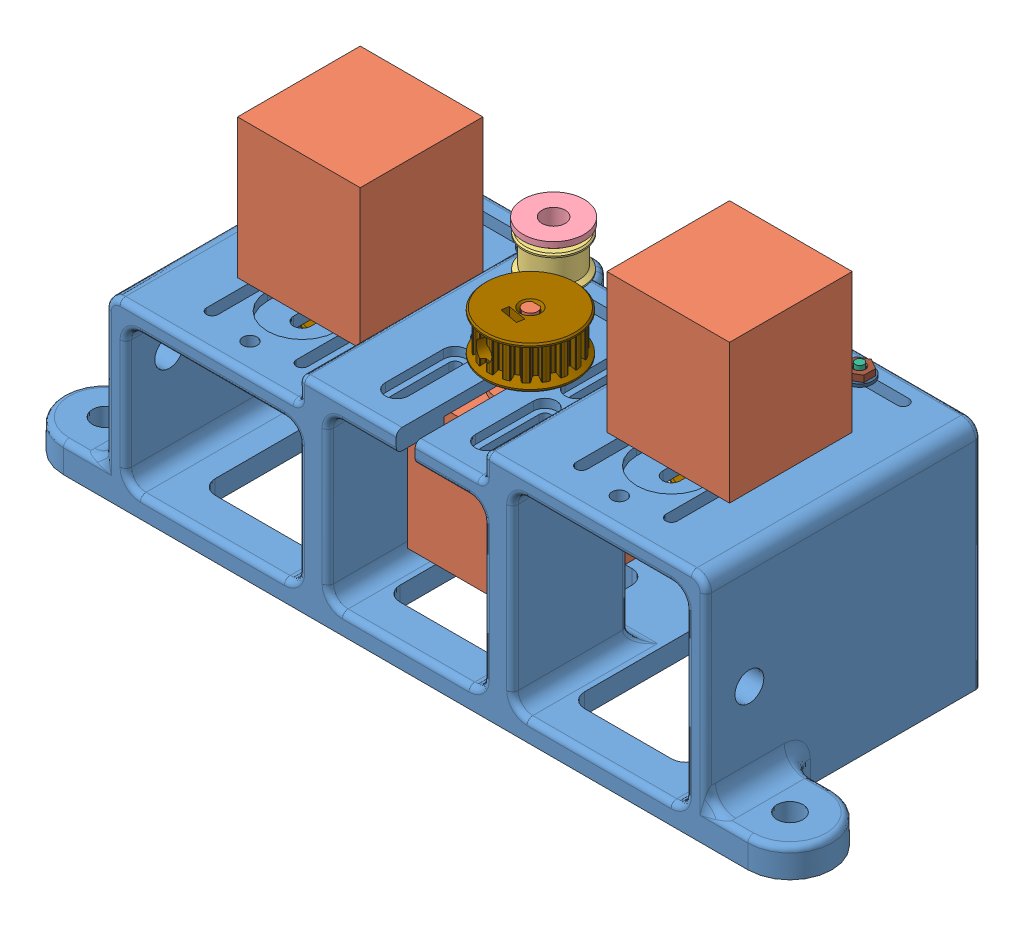
SolidWorks assembly stepper assembly, configuration Default. Lengths in mm.
Overall size (265 127.5 103.75).
53 component instances, 11 part files, 71 mates.
Components (placement in the parent):
- stepper holder for 790-2: stepper holder for 790 [Default] at origin size (265 79.5 95)
- stepper-1: stepper [Default] at (-63.6667 106.5 -0.5) x (1 0 0) z (0 0 -1) size (42.3 72 42.3)
- stepper-2: stepper [Default] at (0 12 4.5) size (42.3 72 42.3)
- stepper-3: stepper [Default] at (63.6667 124 -0.5) x (1 0 0) z (0 0 -1) size (42.3 72 42.3)
- belt tensioner assembly-1: belt tensioner assembly [Default] at (20 67 -23.5) x (-1 0 0) z (0 0 -1) size (27.67 31.4 27.67)
  - belt tensioner pulley-1: belt tensioner pulley [Default] at (0 9.75 0) x (-0.886174 0 0.463352) z (0 -1 0) size (20.5 20.5 12.5)
  - belt tensioner base-1: belt tensioner base [Default] at origin size (21 20 21)
  - M3 METAL washer-1: M3 METAL washer [Default] at (0 4 0) size (7 0.6 7)
  - M3x16 METAL bolt-1: M3x16 METAL bolt [Default] at (0 -11.4 0) x (-0.239711 0 0.970844) z (-0.970844 0 -0.239711) size (5.4 19 5.4)
- belt tensioner assembly-4: belt tensioner assembly [Default] at (-69.5 51.5 -39.5) x (-0.970844 0 -0.239711) z (-0.239711 0 0.970844) size (27.67 31.4 27.67)
  - belt tensioner pulley-1: belt tensioner pulley [Default] at (0 9.75 0) x (-0.886174 0 0.463352) z (0 -1 0) size (20.5 20.5 12.5)
  - belt tensioner base-1: belt tensioner base [Default] at origin size (21 20 21)
  - M3 METAL washer-1: M3 METAL washer [Default] at (0 4 0) size (7 0.6 7)
  - M3x16 METAL bolt-1: M3x16 METAL bolt [Default] at (0 -11.4 0) x (-0.239711 0 0.970844) z (-0.970844 0 -0.239711) size (5.4 19 5.4)
- belt tensioner assembly-6: belt tensioner assembly [Default] at (42.8333 69 -39.5) x (0.970844 0 0.239711) z (0.239711 0 -0.970844) size (27.67 31.4 27.67)
  - belt tensioner pulley-1: belt tensioner pulley [Default] at (0 9.75 0) x (-0.886174 0 0.463352) z (0 -1 0) size (20.5 20.5 12.5)
  - belt tensioner base-1: belt tensioner base [Default] at origin size (21 20 21)
  - M3 METAL washer-1: M3 METAL washer [Default] at (0 4 0) size (7 0.6 7)
  - M3x16 METAL bolt-1: M3x16 METAL bolt [Default] at (0 -11.4 0) x (-0.239711 0 0.970844) z (-0.970844 0 -0.239711) size (5.4 19 5.4)
- belt tensioner assembly-7: belt tensioner assembly [Default] at (69.5 69 -39.5) x (-0.970844 0 -0.239711) z (-0.239711 0 0.970844) size (27.67 31.4 27.67)
  - belt tensioner pulley-1: belt tensioner pulley [Default] at (0 9.75 0) x (-0.886174 0 0.463352) z (0 -1 0) size (20.5 20.5 12.5)
  - belt tensioner base-1: belt tensioner base [Default] at origin size (21 20 21)
  - M3 METAL washer-1: M3 METAL washer [Default] at (0 4 0) size (7 0.6 7)
  - M3x16 METAL bolt-1: M3x16 METAL bolt [Default] at (0 -11.4 0) x (-0.239711 0 0.970844) z (-0.970844 0 -0.239711) size (5.4 19 5.4)
- belt tensioner assembly-8: belt tensioner assembly [Default] at (-42.8333 51.5 -39.5) x (0.239711 0 -0.970844) z (-0.970844 0 -0.239711) size (27.67 31.4 27.67)
  - belt tensioner pulley-1: belt tensioner pulley [Default] at (0 9.75 0) x (-0.886174 0 0.463352) z (0 -1 0) size (20.5 20.5 12.5)
  - belt tensioner base-1: belt tensioner base [Default] at origin size (21 20 21)
  - M3 METAL washer-1: M3 METAL washer [Default] at (0 4 0) size (7 0.6 7)
  - M3x16 METAL bolt-1: M3x16 METAL bolt [Default] at (0 -11.4 0) x (-0.239711 0 0.970844) z (-0.970844 0 -0.239711) size (5.4 19 5.4)
- belt tensioner assembly-9: belt tensioner assembly [Default] at (-20 67 -23.5) x (-0.639531 0 -0.768765) z (0.768765 0 -0.639531) size (27.67 31.4 27.67)
  - belt tensioner pulley-1: belt tensioner pulley [Default] at (0 9.75 0) x (-0.886174 0 0.463352) z (0 -1 0) size (20.5 20.5 12.5)
  - belt tensioner base-1: belt tensioner base [Default] at origin size (21 20 21)
  - M3 METAL washer-1: M3 METAL washer [Default] at (0 4 0) size (7 0.6 7)
  - M3x16 METAL bolt-1: M3x16 METAL bolt [Default] at (0 -11.4 0) x (-0.239711 0 0.970844) z (-0.970844 0 -0.239711) size (5.4 19 5.4)
- M3x12 METAL bolt-1: M3x12 METAL bolt [Default] at (48.1667 83.4 -16) x (0.811733 0 0.584029) z (0.584029 0 -0.811733) size (5.4 15 5.4)
- M3 METAL washer-3: M3 METAL washer [Default] at (48.1667 71.4 -16) size (7 0.6 7)
- M3 METAL washer-4: M3 METAL washer [Default] at (-15.5 64.6 -11) x (-0.514541 0 0.857466) z (0.857466 0 0.514541) size (7 0.6 7)
- M3x8 METAL bolt-2: M3x8 METAL bolt [Default] at (-15.5 56.6 -11) x (-0.864445 0 -0.502727) z (0.502727 0 -0.864445) size (5.6 10.5 5.6)
- stepper pulley-1: stepper pulley [Default] at (0 76.75 4.5) x (-0.98678 0 -0.162068) z (0 -1 0) size (31.3 31.3 14.5)
- stepper pulley-2: stepper pulley [Default] at (63.6667 59.25 -0.5) x (0.991489 0 0.130188) z (0 1 0) size (31.3 31.3 14.5)
- stepper pulley-3: stepper pulley [Default] at (-63.6667 41.75 -0.5) x (-0.606605 0 -0.795004) z (0 1 0) size (31.3 31.3 14.5)
- plain washer 10669 type nl_iso-1: plain washer 10669 type nl_iso [ISO 10669-3.55-N] at (69.5 77 -39.5) x (0 -1 0) z (0 0 1) size (1 9 9)
- plain washer 10669 type nl_iso-2: plain washer 10669 type nl_iso [ISO 10669-3.55-N] at (42.8333 77 -39.5) x (0 -1 0) z (0 0 1) size (1 9 9)
- plain washer 10669 type nl_iso-3: plain washer 10669 type nl_iso [ISO 10669-3.55-N] at (20 59 -23.5) x (0 1 0) z (0 0 1) size (1 9 9)
- plain washer 10669 type nl_iso-4: plain washer 10669 type nl_iso [ISO 10669-3.55-N] at (-20 59 -23.5) x (0 1 0) z (0 0 1) size (1 9 9)
- plain washer 10669 type nl_iso-5: plain washer 10669 type nl_iso [ISO 10669-3.55-N] at (-42.8333 59.5 -39.5) x (0 -1 0) z (0 0 1) size (1 9 9)
- plain washer 10669 type nl_iso-6: plain washer 10669 type nl_iso [ISO 10669-3.55-N] at (-69.5 58.5 -39.5) x (0 1 0) z (0 0 1) size (1 9 9)
- hex thin nut gradeb_iso-1: hex thin nut gradeb_iso [ISO - 4036 - M4 - N] at (69.5 79.2 -39.5) x (1 0 0) z (0 1 0) size (7 8.08 2.2)
- hex thin nut gradeb_iso-2: hex thin nut gradeb_iso [ISO - 4036 - M4 - N] at (42.8333 79.2 -39.5) x (1 0 0) z (0 1 0) size (7 8.08 2.2)
- hex thin nut gradeb_iso-3: hex thin nut gradeb_iso [ISO - 4036 - M4 - N] at (-69.5 61.7 -39.5) x (1 0 0) z (0 1 0) size (7 8.08 2.2)
- hex thin nut gradeb_iso-4: hex thin nut gradeb_iso [ISO - 4036 - M4 - N] at (-42.8333 61.7 -39.5) x (1 0 0) z (0 1 0) size (7 8.08 2.2)
- hex thin nut gradeb_iso-5: hex thin nut gradeb_iso [ISO - 4036 - M4 - N] at (-20 56.8 -23.5) x (1 0 0) z (0 -1 0) size (7 8.08 2.2)
- hex thin nut gradeb_iso-6: hex thin nut gradeb_iso [ISO - 4036 - M4 - N] at (20 56.8 -23.5) x (1 0 0) z (0 -1 0) size (7 8.08 2.2)
Mates (geometry in assembly coordinates):
- Coincident26: coordinate: point of stepper holder-1
- Symmetric1: symmetric aligned: plane of stepper holder for 790-2 through (-51.6667 36 19.5) normal (-1 0 0); plane of stepper holder for 790-2 through (-75.6667 36 19.5) normal (1 0 0); plane of stepper-1 through (-63.6667 106.5 -0.5) normal (1 0 0)
- Coincident27: coincident anti-aligned: plane of stepper holder for 790-2 through (0 58.5 47.5) normal (0 1 0); plane of stepper-1 through (-63.6667 58.5 -0.5) normal (0 -1 0)
- Symmetric4: symmetric aligned: plane of stepper holder for 790-2 through (75.6667 36 19.5) normal (-1 0 0); plane of stepper holder for 790-2 through (51.6667 36 19.5) normal (1 0 0); plane of stepper-3 through (63.6667 124 -0.5) normal (1 0 0)
- Symmetric5: symmetric aligned: plane of stepper holder for 790-2 through (-12 27 19.5) normal (1 0 0); plane of stepper holder for 790-2 through (12 27 19.5) normal (-1 0 0); plane of stepper-2 through (0 12 11.9177) normal (1 0 0)
- Coincident28: coincident anti-aligned: plane of stepper holder for 790-2 through (0 60 47.5) normal (0 -1 0); plane of stepper-2 through (0 60 11.9177) normal (0 1 0)
- Coincident29: coincident anti-aligned: plane of stepper holder for 790-2 through (0 76 47.5) normal (0 1 0); plane of stepper-3 through (63.6667 76 -0.5) normal (0 -1 0)
- Coincident30: coincident anti-aligned: plane of stepper holder for 790-2 through (0 69 47.5) normal (0 -1 0); plane of belt tensioner assembly-6/belt tensioner base-1 through (42.8333 69 -39.5) normal (0 1 0)
- Symmetric7: symmetric aligned: plane of stepper holder for 790-2 through (0 27 -21.5) normal (0 0 -1); plane of stepper holder for 790-2 through (0 27 -25.5) normal (0 0 1); plane of belt tensioner assembly-1 through (20 67 -23.5) normal (0 0 -1)
- Coincident31: coincident anti-aligned: plane of stepper holder for 790-2 through (0 51.5 47.5) normal (0 -1 0); plane of belt tensioner assembly-4/belt tensioner base-1 through (-69.5 51.5 -39.5) normal (0 1 0)
- Coincident32: coincident anti-aligned: plane of stepper holder for 790-2 through (0 67 47.5) normal (0 1 0); plane of belt tensioner assembly-1/belt tensioner base-1 through (20 67 -23.5) normal (0 -1 0)
- Concentric16: concentric anti-aligned: cylinder of stepper-3 through (48.1667 80 -16) axis (0 -1 0) radius 1.5; cylinder of M3x12_bolt-1 through (48.1667 71.4 -16) axis (0 1 0) radius 1.5
- Concentric17: concentric anti-aligned: cylinder of M3x12_bolt-1 through (48.1667 71.4 -16) axis (0 1 0) radius 1.5; cylinder of M3 washer-3 through (48.1667 72 -16) axis (0 -1 0) radius 1.65
- Coincident34: coincident anti-aligned: plane of stepper holder for 790-2 through (0 72 47.5) normal (0 -1 0); plane of M3 washer-3 through (48.1667 72 -16) normal (0 1 0)
- Coincident35: coincident anti-aligned: plane of M3x12_bolt-1 through (48.1667 71.4 -16) normal (0 1 0); plane of M3 washer-3 through (48.1667 71.4 -16) normal (0 -1 0)
- Concentric18: concentric anti-aligned: cylinder of stepper-2 through (0 84 11.9177) axis (0 -1 0) radius 2.5; cylinder of stepper pulley-1 through (0 70.5 11.9177) axis (0 1 0) radius 2.6
- Coincident36: coincident aligned: plane of stepper-2 through (0 84 11.9177) normal (0 1 0); plane of stepper pulley-1 through (0 84 11.9177) normal (0 1 0)
- Concentric21: concentric aligned: cylinder of stepper holder for 790-2 through (84.5 36 -39.5) axis (0 1 0) radius 2; cylinder of belt tensioner assembly-7/M3x16 METAL bolt-1 through (69.5 64.4 -39.5) axis (0 1 0) radius 1.5
- Coincident39: coincident anti-aligned: plane of stepper holder for 790-2 through (0 69 47.5) normal (0 -1 0); plane of belt tensioner assembly-7/belt tensioner base-1 through (69.5 69 -39.5) normal (0 1 0)
- Concentric22: concentric aligned: cylinder of stepper holder for 790-2 through (-84.5 36 -39.5) axis (0 1 0) radius 2; cylinder of belt tensioner assembly-4/M3x16 METAL bolt-1 through (-84.5 46.9 -39.5) axis (0 1 0) radius 1.5
- Coincident40: coincident anti-aligned: plane of stepper holder for 790-2 through (0 51.5 47.5) normal (0 -1 0); plane of belt tensioner assembly-4/belt tensioner base-1 through (-69.5 51.5 -39.5) normal (0 1 0)
- Coincident41: coincident anti-aligned: plane of stepper holder for 790-2 through (0 51.5 47.5) normal (0 -1 0); plane of belt tensioner assembly-8/belt tensioner base-1 through (-42.8333 51.5 -39.5) normal (0 1 0)
- Concentric25: concentric anti-aligned: cylinder of stepper holder for 790-2 through (20 27 -23.5) axis (0 1 0) radius 2; cylinder of belt tensioner assembly-1/M3x16 METAL bolt-1 through (20 71.6 -23.5) axis (0 -1 0) radius 1.5
- Concentric27: concentric anti-aligned: cylinder of stepper holder for 790-2 through (-20 27 -23.5) axis (0 1 0) radius 2; cylinder of belt tensioner assembly-9/M3x16 METAL bolt-1 through (-20 71.6 -23.5) axis (0 -1 0) radius 1.5
- Coincident42: coincident anti-aligned: plane of stepper holder for 790-2 through (0 67 47.5) normal (0 1 0); plane of belt tensioner assembly-9/belt tensioner base-1 through (-20 67 -23.5) normal (0 -1 0)
- Concentric28: concentric aligned: cylinder of stepper holder for 790-2 through (27.8333 26 -39.5) axis (0 1 0) radius 2; cylinder of belt tensioner assembly-6/M3x16 METAL bolt-1 through (42.8333 64.4 -39.5) axis (0 1 0) radius 1.5
- Concentric29: concentric aligned: cylinder of stepper holder for 790-2 through (-27.8333 26 -39.5) axis (0 1 0) radius 2; cylinder of belt tensioner assembly-8/M3x16 METAL bolt-1 through (-42.8333 46.9 -39.5) axis (0 1 0) radius 1.5
- Concentric30: concentric anti-aligned: cylinder of M3 washer-4 through (-15.5 64 -3.5823) axis (0 1 0) radius 1.65; cylinder of M3x8_bolt-2 through (-15.5 64.6 -3.5823) axis (0 -1 0) radius 1.5
- Coincident43: coincident anti-aligned: plane of M3 washer-4 through (-15.5 64.6 -3.5823) normal (0 1 0); plane of M3x8_bolt-2 through (-15.5 64.6 -3.5823) normal (0 -1 0)
- Coincident44: coincident anti-aligned: plane of stepper holder for 790-2 through (0 64 47.5) normal (0 1 0); plane of M3 washer-4 through (-15.5 64 -3.5823) normal (0 -1 0)
- Concentric32: concentric anti-aligned: cylinder of stepper-2 through (-15.5 56 -3.5823) axis (0 1 0) radius 1.5; cylinder of M3x8_bolt-2 through (-15.5 64.6 -3.5823) axis (0 -1 0) radius 1.5
- Concentric33: concentric anti-aligned: cylinder of stepper holder for 790-2 through (63.6667 126.1199 -0.5) axis (0 -1 0) radius 3; cylinder of stepper-3 through (63.6667 52 -0.5) axis (0 1 0) radius 2.5
- Concentric34: concentric anti-aligned: cylinder of stepper holder for 790-2 through (-63.6667 108.6199 -0.5) axis (0 -1 0) radius 3; cylinder of stepper-1 through (-63.6667 34.5 -0.5) axis (0 1 0) radius 2.5
- Concentric35: concentric anti-aligned: cylinder of stepper holder for 790-2 through (0 63 -0.5) axis (0 1 0) radius 3.25; cylinder of stepper-2 through (0 84 -0.5) axis (0 -1 0) radius 2.5
- Concentric36: concentric anti-aligned: cylinder of stepper-3 through (63.6667 52 -0.5) axis (0 1 0) radius 2.5; cylinder of stepper pulley-2 through (63.6667 65.5 -0.5) axis (0 -1 0) radius 2.6
- Coincident46: coincident aligned: plane of stepper-3 through (63.6667 52 -0.5) normal (0 -1 0); plane of stepper pulley-2 through (63.6667 52 -0.5) normal (0 -1 0)
- Concentric37: concentric anti-aligned: cylinder of stepper-1 through (-63.6667 34.5 -0.5) axis (0 1 0) radius 2.5; cylinder of stepper pulley-3 through (-63.6667 48 -0.5) axis (0 -1 0) radius 2.6
- Coincident47: coincident aligned: plane of stepper-1 through (-63.6667 34.5 -0.5) normal (0 -1 0); plane of stepper pulley-3 through (-63.6667 34.5 -0.5) normal (0 -1 0)
- Symmetric8: symmetric aligned: plane of stepper holder for 790-2 through (84.5 36 -37.5) normal (0 0 -1); plane of belt tensioner assembly-7/M3x16 METAL bolt-1 through (84.5 36 -41.5) normal (0 0 1); plane of stepper holder for 790-2 through (69.5 80.4 -39.5) normal (0 0 1)
- Symmetric9: symmetric aligned: plane of stepper holder for 790-2 through (84.5 36 -37.5) normal (0 0 -1); plane of belt tensioner assembly-6/M3x16 METAL bolt-1 through (84.5 36 -41.5) normal (0 0 1); plane of stepper holder for 790-2 through (42.8333 80.4 -39.5) normal (0 0 -1)
- Symmetric10: symmetric aligned: plane of stepper holder for 790-2 through (-84.5 36 -37.5) normal (0 0 -1); plane of belt tensioner assembly-8/M3x16 METAL bolt-1 through (-84.5 36 -41.5) normal (0 0 1); plane of stepper holder for 790-2 through (-42.8333 62.9 -39.5) normal (0 0 1)
- Symmetric11: symmetric aligned: plane of stepper holder for 790-2 through (-84.5 36 -37.5) normal (0 0 -1); plane of belt tensioner assembly-4/M3x16 METAL bolt-1 through (-84.5 36 -41.5) normal (0 0 1); plane of stepper holder for 790-2 through (-69.5 62.9 -39.5) normal (0 0 1)
- Distance8: distance = 15 mm: cylinder of belt tensioner assembly-4/M3x16 METAL bolt-1 through (-69.5 46.9 -39.5) axis (0 1 0) radius 1.5; cylinder of stepper holder for 790-2 through (-84.5 36 -39.5) axis (0 1 0) radius 2
- Distance11: distance = 15 mm: cylinder of stepper holder for 790-2 through (84.5 36 -39.5) axis (0 1 0) radius 2; cylinder of belt tensioner assembly-7/M3x16 METAL bolt-1 through (69.5 64.4 -39.5) axis (0 1 0) radius 1.5
- Distance12: distance = 15 mm: cylinder of stepper holder for 790-2 through (27.8333 26 -39.5) axis (0 1 0) radius 2; cylinder of belt tensioner assembly-6/M3x16 METAL bolt-1 through (42.8333 64.4 -39.5) axis (0 1 0) radius 1.5
- Distance13: distance = 15 mm: cylinder of stepper holder for 790-2 through (-27.8333 26 -39.5) axis (0 1 0) radius 2; cylinder of belt tensioner assembly-8/M3x16 METAL bolt-1 through (-42.8333 46.9 -39.5) axis (0 1 0) radius 1.5
- Concentric42: concentric aligned: cylinder of belt tensioner assembly-7/M3x16 METAL bolt-1 through (69.5 64.4 -39.5) axis (0 1 0) radius 1.5; cylinder of plain washer 10669 type nl_iso-1 through (69.5 76 -39.5) axis (0 1 0) radius 1.775
- Concentric43: concentric aligned: cylinder of belt tensioner assembly-6/M3x16 METAL bolt-1 through (42.8333 64.4 -39.5) axis (0 1 0) radius 1.5; cylinder of plain washer 10669 type nl_iso-2 through (42.8333 76 -39.5) axis (0 1 0) radius 1.775
- Concentric44: concentric aligned: cylinder of belt tensioner assembly-1/M3x16 METAL bolt-1 through (20 71.6 -23.5) axis (0 -1 0) radius 1.5; cylinder of plain washer 10669 type nl_iso-3 through (20 60 -23.5) axis (0 -1 0) radius 1.775
- Concentric45: concentric aligned: cylinder of belt tensioner assembly-9/M3x16 METAL bolt-1 through (-20 71.6 -23.5) axis (0 -1 0) radius 1.5; cylinder of plain washer 10669 type nl_iso-4 through (-20 60 -23.5) axis (0 -1 0) radius 1.775
- Concentric46: concentric aligned: cylinder of belt tensioner assembly-8/M3x16 METAL bolt-1 through (-42.8333 46.9 -39.5) axis (0 1 0) radius 1.5; cylinder of plain washer 10669 type nl_iso-5 through (-42.8333 58.5 -39.5) axis (0 1 0) radius 1.775
- Concentric47: concentric anti-aligned: cylinder of belt tensioner assembly-4/M3x16 METAL bolt-1 through (-69.5 46.9 -39.5) axis (0 1 0) radius 1.5; cylinder of plain washer 10669 type nl_iso-6 through (-69.5 59.5 -39.5) axis (0 -1 0) radius 1.775
- Coincident50: coincident aligned: plane of plain washer 10669 type nl_iso-1 through (69.5 76 -39.5) normal (0 -1 0); plane of plain washer 10669 type nl_iso-2 through (42.8333 76 -39.5) normal (0 -1 0)
- Coincident51: coincident anti-aligned: plane of stepper holder for 790-2 through (0 76 47.5) normal (0 1 0); plane of plain washer 10669 type nl_iso-2 through (42.8333 76 -39.5) normal (0 -1 0)
- Coincident52: coincident aligned: plane of plain washer 10669 type nl_iso-5 through (-42.8333 58.5 -39.5) normal (0 -1 0); plane of plain washer 10669 type nl_iso-6 through (-69.5 58.5 -39.5) normal (0 -1 0)
- Coincident54: coincident anti-aligned: plane of stepper holder for 790-2 through (0 58.5 47.5) normal (0 1 0); plane of plain washer 10669 type nl_iso-5 through (-42.8333 58.5 -39.5) normal (0 -1 0)
- Coincident55: coincident aligned: plane of plain washer 10669 type nl_iso-3 through (20 60 -23.5) normal (0 1 0); plane of plain washer 10669 type nl_iso-4 through (-20 60 -23.5) normal (0 1 0)
- Coincident56: coincident anti-aligned: plane of stepper holder for 790-2 through (0 60 47.5) normal (0 -1 0); plane of plain washer 10669 type nl_iso-4 through (-20 60 -23.5) normal (0 1 0)
- Concentric50: concentric aligned: cylinder of plain washer 10669 type nl_iso-1 through (69.5 76 -39.5) axis (0 1 0) radius 1.775; cylinder of hex thin nut gradeb_iso-1 through (69.5 54.1625 -39.5) axis (0 1 0) radius 2
- Coincident59: coincident anti-aligned: plane of plain washer 10669 type nl_iso-1 through (69.5 77 -39.5) normal (0 1 0); plane of hex thin nut gradeb_iso-1 through (62.5 77 -39.5) normal (0 -1 0)
- Concentric51: concentric aligned: cylinder of plain washer 10669 type nl_iso-2 through (42.8333 76 -39.5) axis (0 1 0) radius 1.775; cylinder of hex thin nut gradeb_iso-2 through (42.8333 54.1625 -39.5) axis (0 1 0) radius 2
- Coincident60: coincident anti-aligned: plane of plain washer 10669 type nl_iso-2 through (42.8333 77 -39.5) normal (0 1 0); plane of hex thin nut gradeb_iso-2 through (35.8333 77 -39.5) normal (0 -1 0)
- Concentric52: concentric anti-aligned: cylinder of plain washer 10669 type nl_iso-6 through (-69.5 59.5 -39.5) axis (0 -1 0) radius 1.775; cylinder of hex thin nut gradeb_iso-3 through (-69.5 36.6625 -39.5) axis (0 1 0) radius 2
- Coincident61: coincident anti-aligned: plane of plain washer 10669 type nl_iso-6 through (-69.5 59.5 -39.5) normal (0 1 0); plane of hex thin nut gradeb_iso-3 through (-76.5 59.5 -39.5) normal (0 -1 0)
- Concentric53: concentric aligned: cylinder of plain washer 10669 type nl_iso-5 through (-42.8333 58.5 -39.5) axis (0 1 0) radius 1.775; cylinder of hex thin nut gradeb_iso-4 through (-42.8333 36.6625 -39.5) axis (0 1 0) radius 2
- Coincident62: coincident anti-aligned: plane of plain washer 10669 type nl_iso-5 through (-42.8333 59.5 -39.5) normal (0 1 0); plane of hex thin nut gradeb_iso-4 through (-49.8333 59.5 -39.5) normal (0 -1 0)
- Concentric54: concentric aligned: cylinder of plain washer 10669 type nl_iso-4 through (-20 60 -23.5) axis (0 -1 0) radius 1.775; cylinder of hex thin nut gradeb_iso-5 through (-20 81.8375 -23.5) axis (0 -1 0) radius 2
- Coincident63: coincident anti-aligned: plane of plain washer 10669 type nl_iso-4 through (-20 59 -23.5) normal (0 -1 0); plane of hex thin nut gradeb_iso-5 through (-27 59 -23.5) normal (0 1 0)
- Concentric55: concentric aligned: cylinder of plain washer 10669 type nl_iso-3 through (20 60 -23.5) axis (0 -1 0) radius 1.775; cylinder of hex thin nut gradeb_iso-6 through (20 81.8375 -23.5) axis (0 -1 0) radius 2
- Coincident64: coincident anti-aligned: plane of plain washer 10669 type nl_iso-3 through (20 59 -23.5) normal (0 -1 0); plane of hex thin nut gradeb_iso-6 through (13 59 -23.5) normal (0 1 0)
- Distance14: distance = 5 mm: cylinder of stepper holder for 790-2 through (0 63 -0.5) axis (0 1 0) radius 3.25; cylinder of stepper-2 through (0 84 4.5) axis (0 -1 0) radius 2.5
